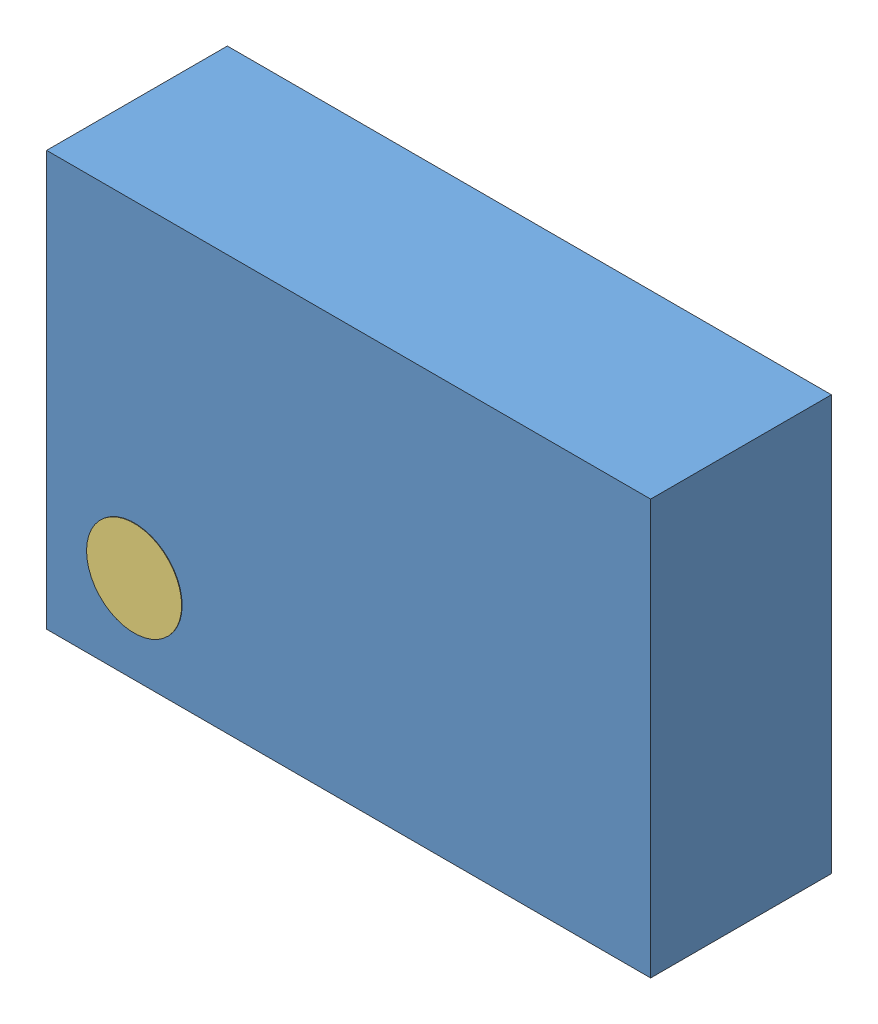
SolidWorks assembly User Library-dsbga_12, configuration Default. Lengths in mm.
Overall size (1.27 0.87 0.55).
17 component instances, 3 part files, 0 mates.
Components (placement in the parent):
- User Library-dsbga_12_Free-Models-1: User Library-dsbga_12_Free-Models [Default] at origin size (1.27 0.87 0.55)
  - User Library-dsbga_12_582294864-1: User Library-dsbga_12_582294864 [Default] at (0.0001 0.0001 0.17) size (1.27 0.87 0.38)
    - User Library-dsbga_12_Extruded-1: User Library-dsbga_12_Extruded [Default] at origin size (1.27 0.87 0.38)
  - User Library-dsbga_12_582411960-1: User Library-dsbga_12_582411960 [Default] at (-0.3999 0.2001 0.125) size (0.24 0.24 0.24)
    - User Library-dsbga_12_Sphere-1: User Library-dsbga_12_Sphere [Default] at origin size (0.24 0.24 0.24)
  - User Library-dsbga_12_582411960-2: User Library-dsbga_12_582411960 [Default] at (0.0001 0.2001 0.125) size (0.24 0.24 0.24)
    - User Library-dsbga_12_Sphere-1: User Library-dsbga_12_Sphere [Default] at origin size (0.24 0.24 0.24)
  - User Library-dsbga_12_582411960-3: User Library-dsbga_12_582411960 [Default] at (0.4001 0.2001 0.125) size (0.24 0.24 0.24)
    - User Library-dsbga_12_Sphere-1: User Library-dsbga_12_Sphere [Default] at origin size (0.24 0.24 0.24)
  - User Library-dsbga_12_582411960-4: User Library-dsbga_12_582411960 [Default] at (0.4001 -0.1999 0.125) size (0.24 0.24 0.24)
    - User Library-dsbga_12_Sphere-1: User Library-dsbga_12_Sphere [Default] at origin size (0.24 0.24 0.24)
  - User Library-dsbga_12_582411960-5: User Library-dsbga_12_582411960 [Default] at (0.0001 -0.1999 0.125) size (0.24 0.24 0.24)
    - User Library-dsbga_12_Sphere-1: User Library-dsbga_12_Sphere [Default] at origin size (0.24 0.24 0.24)
  - User Library-dsbga_12_582411960-6: User Library-dsbga_12_582411960 [Default] at (-0.3999 -0.1999 0.125) size (0.24 0.24 0.24)
    - User Library-dsbga_12_Sphere-1: User Library-dsbga_12_Sphere [Default] at origin size (0.24 0.24 0.24)
  - User Library-dsbga_12_582412080-1: User Library-dsbga_12_582412080 [Default] at (-0.4499 -0.2499 0.2) size (0.2 0.2 0.35)
    - User Library-dsbga_12_Cylinder-1: User Library-dsbga_12_Cylinder [Default] at origin size (0.2 0.2 0.35)
